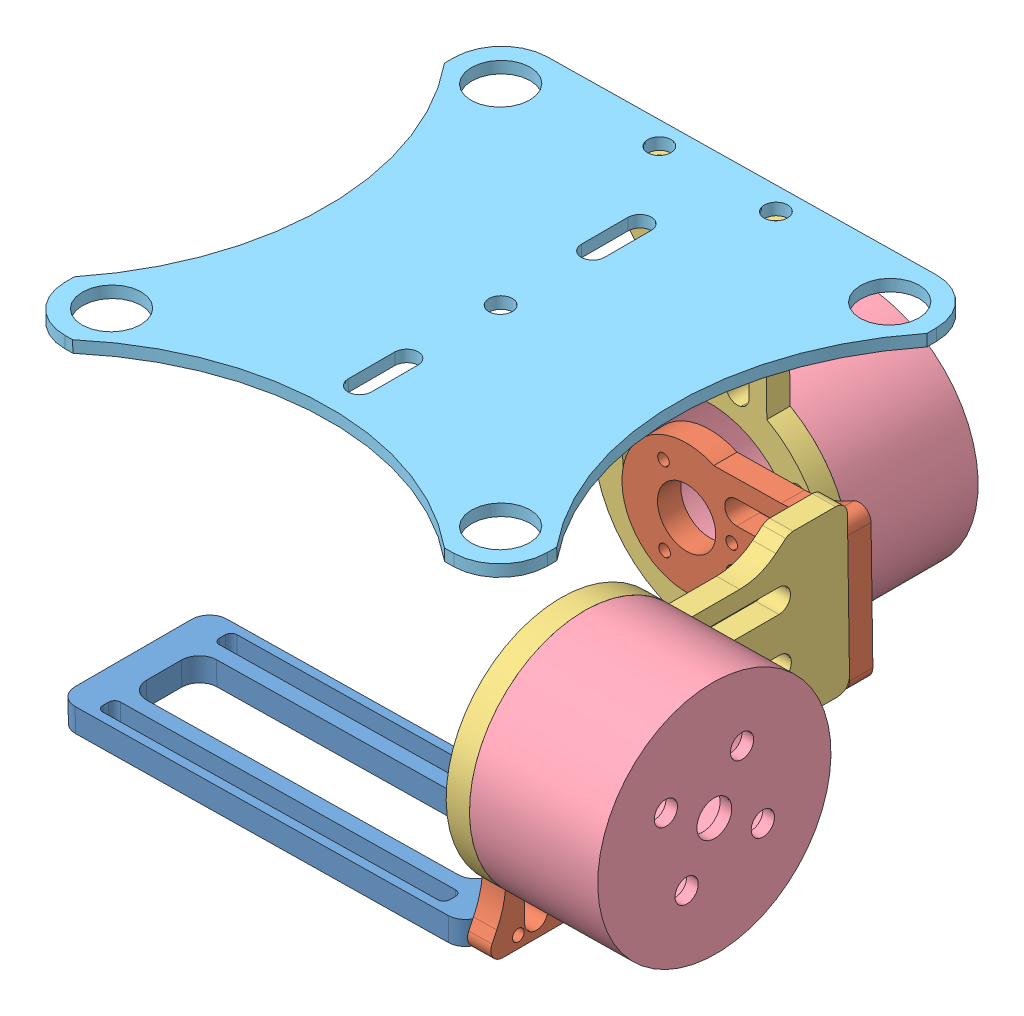
SolidWorks assembly Gymbal, configuration Default. Lengths in mm.
Overall size (99.97 75.78 102.73).
8 component instances, 5 part files, 19 mates.
Components (placement in the parent):
- Camera hold-1: Camera hold [Default] at (-14.8239 -26.0063 49) x (0.999891 0.014771 0) z (0 0 1) size (70 4 26)
- Motor1_below-1: Motor1_below [Default] at (23.7613 2.3603 49) x (0 0 1) z (-0.999891 -0.014771 0) size (25.45 38.89 4)
- Motor1_hoder-1: Motor1_hoder [Default] at (0 0 -4) x (-0.999891 -0.014771 0) z (0 0 1) size (40 65 4)
- Motor1_in-1: Motor1_in [Default] at (47.7587 2.7148 49) x (0.014619 -0.98964 -0.142822) z (-0.00211 0.142806 -0.989748) size (40 22 40)
- Motor1_in-2: Motor1_in [Default] at (0 0 -24) x (-0.639997 -0.768377 0) z (-0.768377 0.639997 0) size (40 22 40)
- Motor1_hoder-2: Motor1_hoder [Default] at (23.7613 2.3603 49) x (-0.014771 0.999891 0) z (0.999891 0.014771 0) size (40 65 4)
- Motor1_below-2: Motor1_below [Default] x (-0.014771 0.999891 0) z (0 0 1) size (25.45 38.89 4)
- Plate_gimbal-1: Plate_gimbal [Default] at (-0.5078 44.9974 35.3613) x (-0.999891 -0.014771 0) z (0 0 -1) size (82.74 2 82.74)
Mates (geometry in assembly coordinates):
- Coincident1: coincident anti-aligned: plane of Camera hold-1 through (20.1132 -21.4898 59) normal (0.999891 0.014771 0); plane of Motor1_below-1 through (19.7618 2.3013 49) normal (-0.999891 -0.014771 0)
- Concentric1: concentric aligned: cylinder of Motor1_below-1 through (19.7618 2.3013 49) axis (0.999891 0.014771 0) radius 5; cylinder of Motor1_in-1 through (27.7609 2.4194 49) axis (0.999891 0.014771 0) radius 15
- Coincident5: coincident anti-aligned: plane of Motor1_in-1 through (27.7609 2.4194 49) normal (-0.999891 -0.014771 0); plane of Motor1_hoder-2 through (27.7609 2.4194 49) normal (0.999891 0.014771 0)
- Concentric2: concentric anti-aligned: cylinder of Motor1_in-1 through (27.7609 2.4194 49) axis (0.999891 0.014771 0) radius 15; cylinder of Motor1_hoder-2 through (27.7609 2.4194 49) axis (-0.999891 -0.014771 0) radius 15
- Coincident7: coincident anti-aligned: plane of Motor1_below-1 through (23.7613 2.3603 49) normal (0.999891 0.014771 0); plane of Motor1_hoder-2 through (23.7613 2.3603 49) normal (-0.999891 -0.014771 0)
- Coincident8: coincident anti-aligned: plane of Motor1_hoder-2 through (27.5837 14.4181 4) normal (0 0 -1); plane of Motor1_below-2 through (0 0 4) normal (0 0 1)
- Coincident10: coincident anti-aligned: plane of Motor1_hoder-1 through (0 0 -4) normal (0 0 -1); plane of Motor1_in-2 through (0 0 -4) normal (0 0 1)
- Concentric7: concentric aligned: cylinder of Motor1_hoder-1 through (0 0 0) axis (0 0 -1) radius 20; cylinder of Motor1_in-2 through (0 0 -4) axis (0 0 -1) radius 20
- Coincident11: coincident anti-aligned: plane of Motor1_hoder-1 through (0 0 0) normal (0 0 1); plane of Motor1_below-2 through (0 0 0) normal (0 0 -1)
- Concentric8: concentric aligned: cylinder of Motor1_hoder-1 through (0 0 0) axis (0 0 -1) radius 15; cylinder of Motor1_below-2 through (0 0 4) axis (0 0 -1) radius 5
- Concentric9: concentric aligned: cylinder of Motor1_hoder-2 through (25.909 -7.6181 8) axis (0 0 -1) radius 1; cylinder of Motor1_below-2 through (25.909 -7.6181 4) axis (0 0 -1) radius 1
- Concentric10: concentric aligned: cylinder of Camera hold-1 through (15.1433 -23.5634 57) axis (0.999891 0.014771 0) radius 1; cylinder of Motor1_below-1 through (20.1428 -23.4895 57) axis (0.999891 0.014771 0) radius 1
- Concentric11: concentric: cylinder of Motor1_below-2 through (0 0 4) axis (0 0 -1) radius 5
- Concentric16: concentric aligned: cylinder of Camera hold-1 through (15.1433 -23.5634 41) axis (0.999891 0.014771 0) radius 1; cylinder of Motor1_below-1 through (20.1428 -23.4895 41) axis (0.999891 0.014771 0) radius 1
- Parallel1: parallel aligned: plane of Camera hold-1 through (-46.8795 -22.4794 62) normal (0 0 1); plane of Motor1_hoder-1 through (0 0 0) normal (0 0 1)
- Parallel4: parallel aligned: plane of Motor1_hoder-1 through (-12.6634 44.8178 0) normal (-0.014771 0.999891 0); plane of Motor1_below-2 through (4.6497 10.0698 4) normal (-0.014771 0.999891 0)
- Concentric17: concentric: cylinder of Motor1_hoder-1 through (-10.5954 40.848 -2) axis (-0.014771 0.999891 0) radius 1; cylinder of Plate_gimbal-1 through (-10.684 46.8473 -2) axis (0.014771 -0.999891 0) radius 2
- Concentric18: concentric: cylinder of Motor1_hoder-1 through (9.4024 41.1434 -2) axis (-0.014771 0.999891 0) radius 1; cylinder of Plate_gimbal-1 through (9.3138 47.1427 -2) axis (0.014771 -0.999891 0) radius 2
- Coincident12: coincident anti-aligned: plane of Motor1_hoder-1 through (-12.6634 44.8178 0) normal (-0.014771 0.999891 0); plane of Plate_gimbal-1 through (-80.4991 43.8158 35.3613) normal (0.014771 -0.999891 0)
